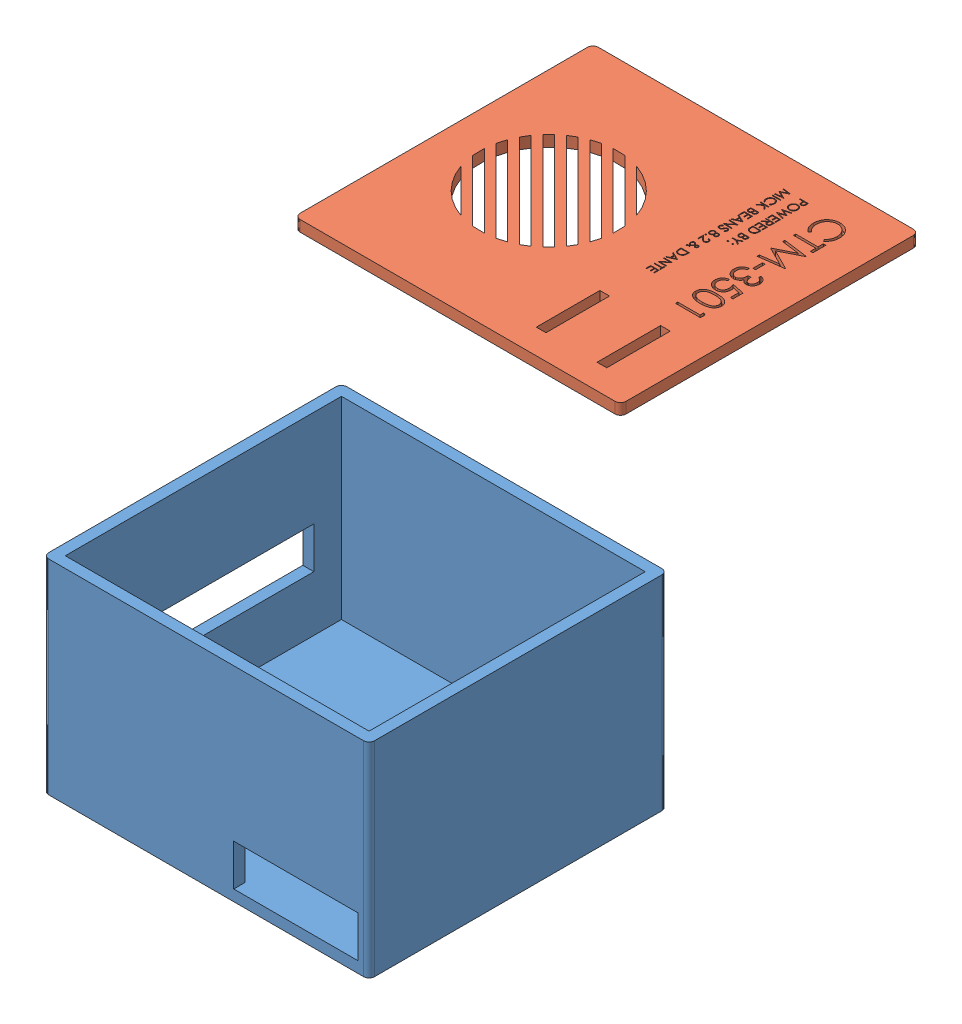
SolidWorks assembly boxass, configuration Default. Lengths in mm.
Overall size (157.54 95.37 238.6).
2 component instances, 2 part files, 0 mates.
Components (placement in the parent):
- box-1: box [Default] at (-2.2149 23.3576 138.6827) size (118 74 108)
- lid-1: lid [Default] at (17.2464 114.7283 -45.9193) size (118 8 108)
